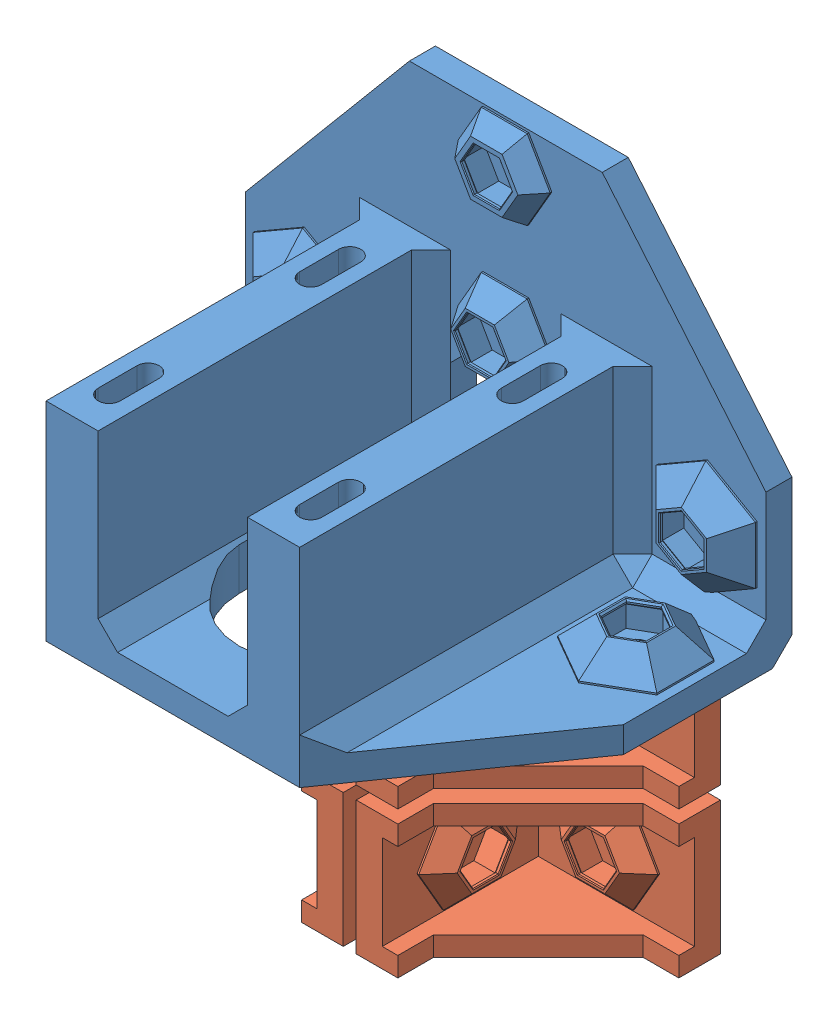
SolidWorks assembly motor-bracket-plate-3x, configuration Default. Lengths in mm.
Overall size (80 111.12 55.2).
5 component instances, 2 part files, 14 mates.
Components (placement in the parent):
- motor-bracket-1: motor-bracket [Default] at (0 2096.271 0) x (0 -1 0) z (-1 0 0) size (54 55.2 80)
- window-bracket-single-1: window-bracket-single [Default] at (164.4567 1734.1364 90) x (-0.5 0.866025 0) z (0.866025 0.5 0) size (31.75 28 34.5)
- window-bracket-single-2: window-bracket-single [Default] at (-164.4567 1958.9056 90) x (0.5 -0.866025 0) z (-0.866025 -0.5 0) size (31.75 28 34.5)
- window-bracket-single-3: window-bracket-single [Default] at (164.4567 1756.6364 90) x (-0.5 0.866025 0) z (0.866025 0.5 0) size (31.75 28 34.5)
- window-bracket-single-4: window-bracket-single [Default] at (-164.4567 1981.4056 90) x (0.5 -0.866025 0) z (-0.866025 -0.5 0) size (31.75 28 34.5)
Mates (geometry in assembly coordinates):
- Coincident3: coincident aligned: plane of window-bracket-single-1 through (-16.3205 1856.771 0) normal (0 1 0); plane of window-bracket-single-2 through (-29 1856.771 28) normal (0 1 0)
- Distance3: distance = 2 mm anti-aligned: plane of window-bracket-single-2 through (-1 1958.9056 90) normal (1 0 0); plane of window-bracket-single-1 through (1 1734.1364 90) normal (-1 0 0)
- Coincident5: coincident aligned: plane of motor-bracket-1 through (-40 5261.6036 0) normal (0 0 -1); plane of window-bracket-single-2 through (-91 1958.9056 0) normal (0 0 -1)
- Coincident6: coincident aligned: plane of motor-bracket-1 through (-40 5261.6036 0) normal (0 0 -1); plane of window-bracket-single-1 through (91 1734.1364 0) normal (0 0 -1)
- Coincident10: coincident aligned: plane of window-bracket-single-1 through (91 1734.1364 0) normal (0 0 -1); plane of window-bracket-single-3 through (91 1756.6364 0) normal (0 0 -1)
- Coincident11: coincident aligned: plane of window-bracket-single-2 through (-91 1958.9056 0) normal (0 0 -1); plane of window-bracket-single-4 through (-91 1981.4056 0) normal (0 0 -1)
- Coincident12: coincident aligned: plane of window-bracket-single-2 through (-1 1958.9056 90) normal (1 0 0); plane of window-bracket-single-4 through (-1 1981.4056 90) normal (1 0 0)
- Coincident13: coincident aligned: plane of window-bracket-single-1 through (1 1734.1364 90) normal (-1 0 0); plane of window-bracket-single-3 through (1 1756.6364 90) normal (-1 0 0)
- Coincident14: coincident aligned: plane of window-bracket-single-3 through (29 1858.771 28) normal (0 -1 0); plane of window-bracket-single-4 through (16.3205 1858.771 0) normal (0 -1 0)
- Distance4: distance = 2 mm anti-aligned: plane of window-bracket-single-3 through (29 1858.771 28) normal (0 -1 0); plane of window-bracket-single-1 through (-16.3205 1856.771 0) normal (0 1 0)
- Symmetric2: symmetric aligned: plane of window-bracket-single-1 through (1 1734.1364 90) normal (-1 0 0); plane of window-bracket-single-2 through (-1 1958.9056 90) normal (1 0 0); plane of assembly through (0 0 0) normal (1 0 0)
- Coincident16: coincident anti-aligned: plane of motor-bracket-1 through (0 5472.6036 0) normal (-1 0 0); plane of assembly through (0 0 0) normal (1 0 0)
- Coincident17: coincident anti-aligned: plane of motor-bracket-1 through (-40 1885.271 0) normal (0 0 -1); plane of assembly
- Distance5: distance = 2 mm anti-aligned: plane of window-bracket-single-4 through (-29 1879.271 28) normal (0 1 0); plane of motor-bracket-1 through (0 1881.271 0) normal (0 -1 0)
